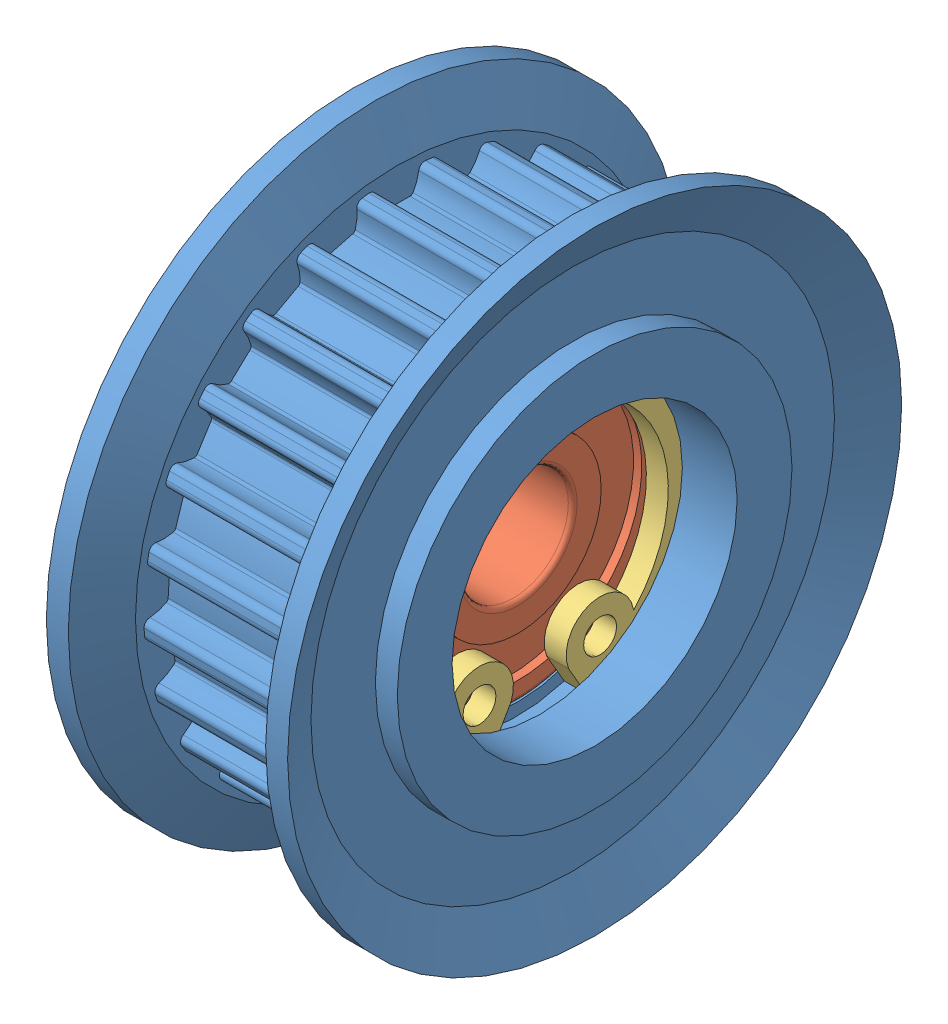
SolidWorks assembly Assem3, configuration Default. Lengths in mm.
Overall size (11 28 28).
3 component instances, 3 part files, 0 mates.
Components (placement in the parent):
- AHTF25S3M060flanged_idlers-1: AHTF25S3M060flanged_idlers [Default] at origin size (11 28 28)
- B695ZZ-1: B695ZZ [Default] at (2 0 0) x (-1 0 0) z (0 0 1) size (4 13 13)
- RTWS13-1: RTWS13 [Default] at (2.5 0 0) size (1 13.78 14.1)
